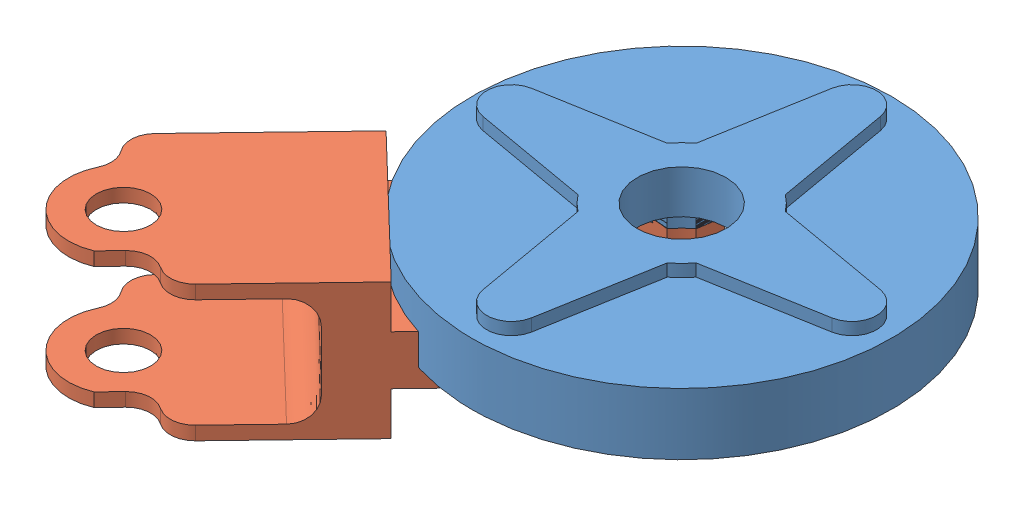
SolidWorks assembly Servo Cap, configuration Default. Lengths in mm.
Overall size (61.69 13.97 62.71).
2 component instances, 2 part files, 2 mates.
Components (placement in the parent):
- Servo Cap Lower Half-1: Servo Cap Lower Half [Default] at (-80.0498 3.6288 37.6188) size (43.18 7.62 43.18)
- servo arm-1: servo arm [Default] at (-80.0498 -2.7212 37.6188) x (-0.693059 0 0.720881) z (-0.720881 0 -0.693059) size (56.49 13.97 20.96)
Mates (geometry in assembly coordinates):
- Coincident1: coincident: axis of Servo Cap Lower Half-1 through (-80.0498 11.2488 37.6188) axis (0 -1 0); axis of servo arm-1 through (-80.0498 6.8038 37.6188) axis (0 -1 0)
- Coincident5: coincident anti-aligned: plane of Servo Cap Lower Half-1 through (-80.0498 6.8038 37.6188) normal (0 -1 0); plane of servo arm-1 through (-73.1834 6.8038 44.2202) normal (0 1 0)
